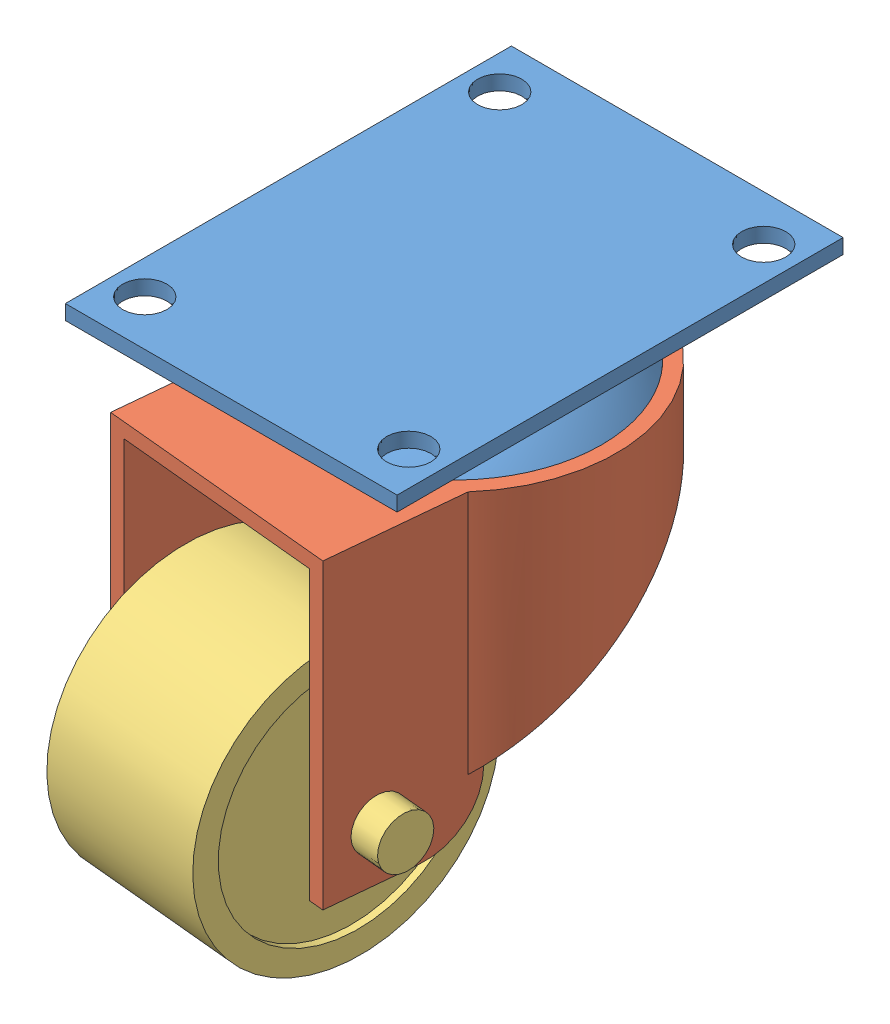
SolidWorks assembly assem_caster, configuration Default. Lengths in mm.
Overall size (48.88 70.33 81.97).
3 component instances, 3 part files, 4 mates.
Components (placement in the parent):
- casterMountingPlate-1: casterMountingPlate [Default] at (18.5848 38.712 45.8952) size (45 10.47 60.5)
- casterSwivel-1: casterSwivel [Default] at (18.5848 -9.7561 45.8952) x (0.095884 0 -0.995393) z (0.995393 0 0.095884) size (53 41 44)
- casterWheel-1: casterWheel [Default] at (8.1134 -3.7561 68.9976) x (0.046117 0.87674 -0.478748) z (0.084065 -0.480964 -0.872701) size (38.1 40 38.1)
Mates (geometry in assembly coordinates):
- Concentric1: concentric: circle of casterMountingPlate-1; circle of casterSwivel-1
- Coincident1: coincident: plane of casterMountingPlate-1 through (18.5848 30.2439 45.8952) normal (0 -1 0); plane of casterSwivel-1 through (18.5848 30.2439 45.8952) normal (0 1 0)
- Concentric2: concentric: circle of casterSwivel-1; cylinder of casterWheel-1 through (37.9751 -3.7561 71.8741) axis (-0.995393 0 -0.095884) radius 3.5
- Distance2: distance = 4 mm: plane of casterWheel-1 through (28.0212 -3.7561 70.9153) normal (0.995393 0 0.095884); plane of casterSwivel-1 through (33.2493 28.2439 58.3587) normal (-0.995393 0 -0.095884)
